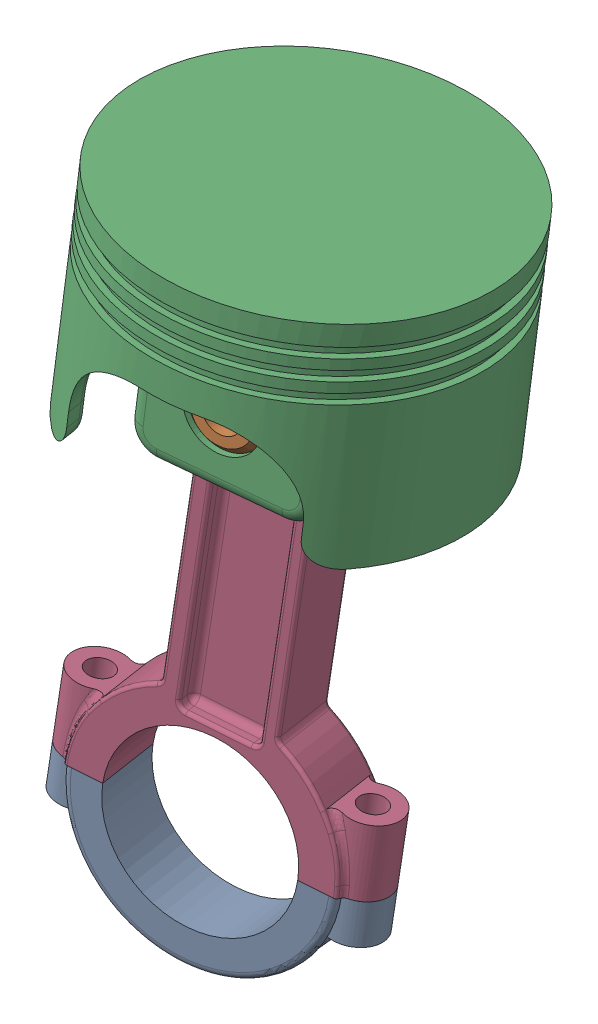
SolidWorks assembly Assem1, configuration Default. Lengths in mm.
Overall size (154.7 267.13 153.7).
4 component instances, 4 part files, 7 mates.
Components (placement in the parent):
- Cap Rod Piston-1: Cap Rod Piston [Default] at (121.5158 -135.305 86.4667) x (0.976835 -0.106149 -0.185811) z (-0.191959 -0.050896 -0.980082) size (108.4 44.45 24.13)
- Pin Piston-1: Pin Piston [Default] at (130.2897 14.1419 41.4037) x (-0.672688 0.733977 0.093637) z (0.191959 0.050896 0.980082) size (25.4 25.4 69.85)
- Piston-1: Piston [Default] at (141.1558 72.7398 71.8213) x (-0.191959 -0.050896 -0.980082) z (0.978681 -0.084252 -0.187309) size (127 82.5 127)
- Rod Piston 2-1: Rod Piston 2 [Default] at (136.9843 15.9169 75.584) x (-0.094578 -0.993047 0.070093) z (-0.191959 -0.050896 -0.980082) size (190.5 108.4 31.75)
Mates (geometry in assembly coordinates):
- Concentric2: concentric aligned: cylinder of Piston-1 through (124.7958 12.6852 13.3537) axis (0.191959 0.050896 0.980082) radius 12.7; cylinder of Rod Piston 2-1 through (134.6683 15.3028 63.7594) axis (0.191959 0.050896 0.980082) radius 25.4
- Coincident1: coincident anti-aligned: plane of Piston-1 through (132.0817 -10.1677 61.7012) normal (0.191959 0.050896 0.980082); plane of Rod Piston 2-1 through (133.9369 15.1089 60.0252) normal (-0.191959 -0.050896 -0.980082)
- Concentric3: concentric anti-aligned: cylinder of Pin Piston-1 through (143.6981 17.697 109.8624) axis (-0.191959 -0.050896 -0.980082) radius 12.7; cylinder of Piston-1 through (124.7958 12.6852 13.3537) axis (0.191959 0.050896 0.980082) radius 12.7
- Coincident2: coincident aligned: plane of Pin Piston-1 through (130.2897 14.1419 41.4037) normal (-0.191959 -0.050896 -0.980082); plane of Piston-1 through (128.4345 -11.1348 43.0797) normal (-0.191959 -0.050896 -0.980082)
- Coincident3: coincident anti-aligned: plane of Cap Rod Piston-1 through (150.2143 -139.2893 68.7425) normal (0.094578 0.993047 -0.070093); plane of Rod Piston 2-1 through (120.255 -136.0337 74.4413) normal (-0.094578 -0.993047 0.070093)
- Concentric4: concentric aligned: cylinder of Cap Rod Piston-1 through (76.6532 -145.7306 95.7949) axis (-0.094578 -0.993047 0.070093) radius 4.76; cylinder of Rod Piston 2-1 through (80.4977 -105.3633 92.9456) axis (-0.094578 -0.993047 0.070093) radius 4.76
- Concentric5: concentric aligned: cylinder of Cap Rod Piston-1 through (163.4938 -155.1673 79.2763) axis (-0.094578 -0.993047 0.070093) radius 4.76; cylinder of Rod Piston 2-1 through (167.3384 -114.7999 76.427) axis (-0.094578 -0.993047 0.070093) radius 4.76
